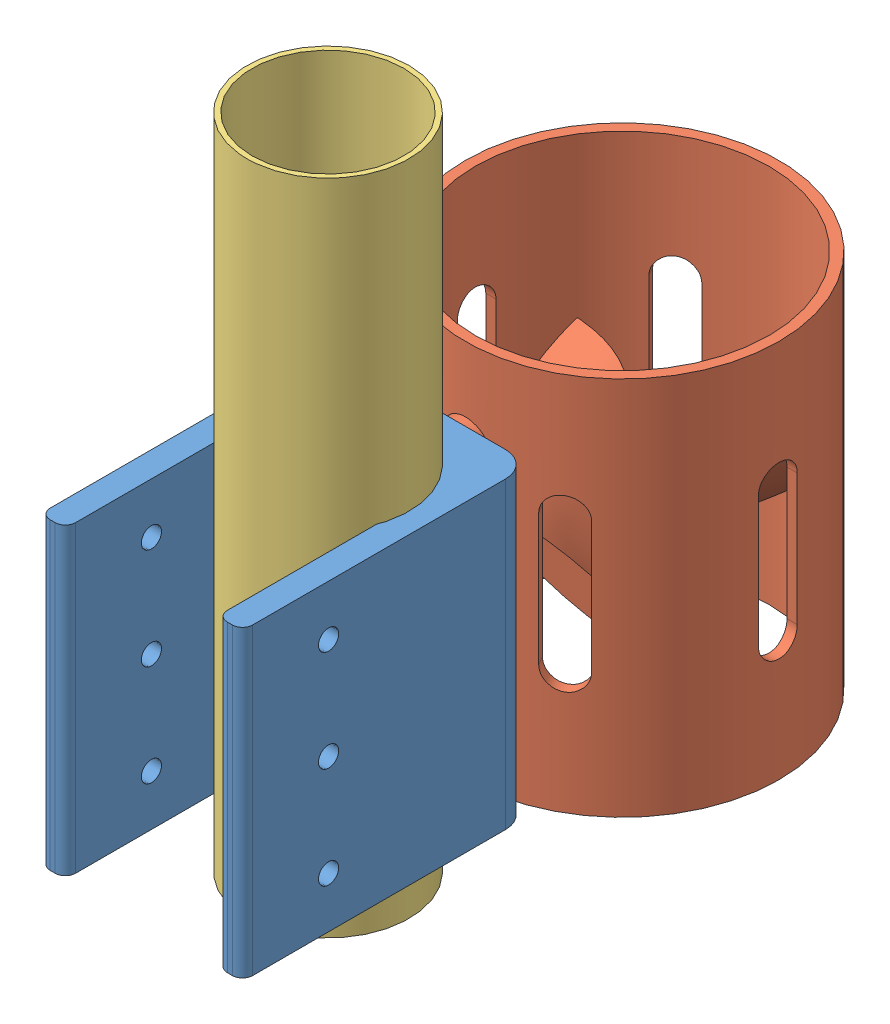
SolidWorks assembly 装配体2电机+固定夹子, configuration 默认. Lengths in mm.
Overall size (62 130 126).
3 component instances, 3 part files, 3 mates.
Components (placement in the parent):
- 零件2电机固定夹子-1: 零件2电机固定夹子 [默认] at (8.8034 -33.0559 45.5203) size (40 60 57)
- 零件1-无刷电机-1: 零件1-无刷电机 [默认] at (-9.4852 -40.5559 -6.5) x (0 0 1) z (-1 0 0) size (69 75 62)
- 零件4纵向32mm管子-1: 零件4纵向32mm管子 [默认] at (-9.4852 -42.7508 51.6135) size (32 130 32)
Mates (geometry in assembly coordinates):
- 重合1: coincident: circle of assembly; circle of assembly; circle of 零件2电机固定夹子-1; circle of 零件1-无刷电机-1
- 同心1: concentric: circle of assembly; circle of assembly; circle of 零件2电机固定夹子-1; circle of 零件1-无刷电机-1
- 同心2: concentric: cylinder of assembly; cylinder of assembly; cylinder of 零件2电机固定夹子-1 through (-9.4852 26.9441 51.6135) axis (0 -1 0) radius 15; cylinder of 零件4纵向32mm管子-1 through (-9.4852 87.2492 51.6135) axis (0 -1 0) radius 16
